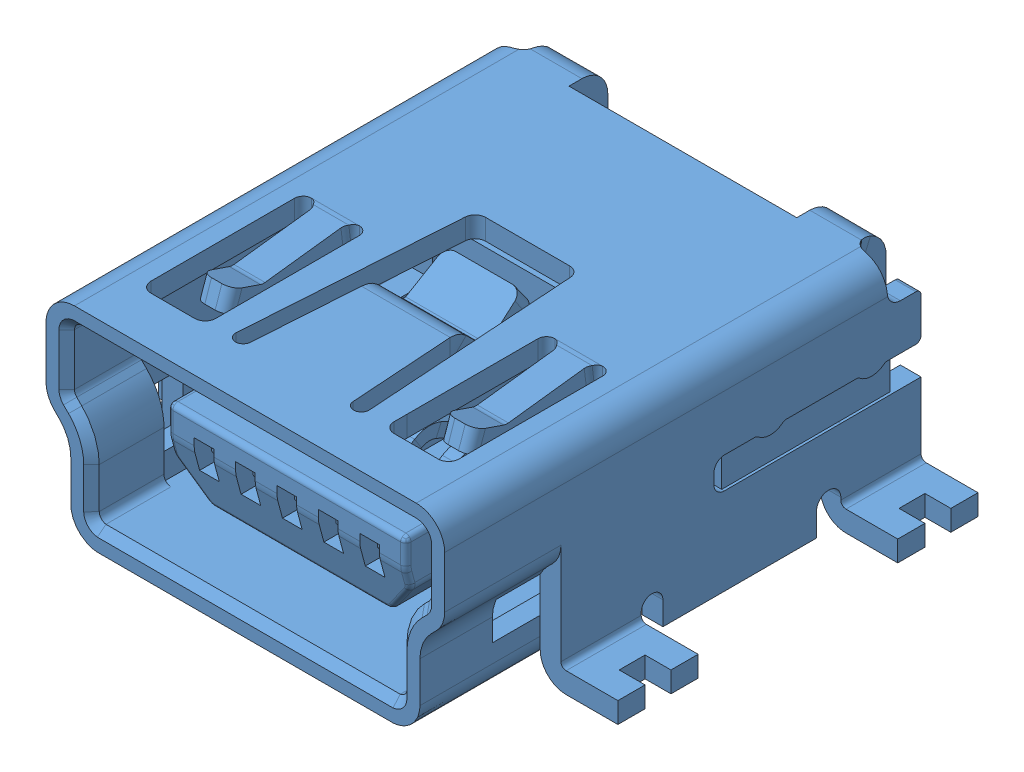
SolidWorks assembly i10033526 , configuration Default. Lengths in mm.
Overall size (9.91 7.33 9.41).
4 component instances, 1 part files, 0 mates.
Components (placement in the parent):
- i10033526 .igs-1: i10033526 .igs [Default] at origin size (9.91 7.33 9.41)
  - Assembly-1_Asm_2.igs-1: Assembly-1_Asm_2.igs [Default] at origin size (9.91 7.33 9.41)
    - Assembly-1_Asm_1.igs-1: Assembly-1_Asm_1.igs [Default] at origin size (9.91 7.33 9.41)
      - 1.2.igs-1: 1.2.igs [Default] at (-23.7846 7.788 -0.7181) size (9.91 7.33 9.41)
